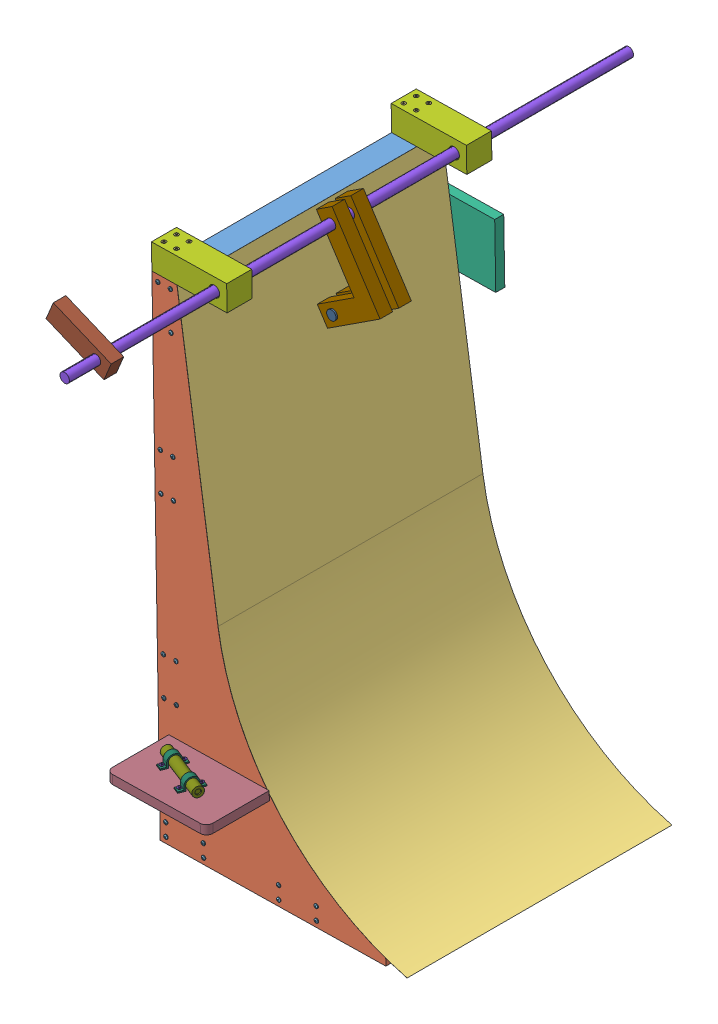
SolidWorks assembly Ramp System, configuration Default. Lengths in mm.
Overall size (518.53 1077.79 1143).
89 component instances, 19 part files, 30 mates.
Components (placement in the parent):
- Ramp-1: Ramp [Default] at (68.598 121.8193 472.884) size (517.11 999.07 560.24)
  - base support-1: base support [Default] at (50.3599 26.2618 18.2563) x (0.999855 0.017038 0) z (0 0 1) size (101.6 50.8 500)
  - base support-2: base support [Default] at (278.9267 30.1567 18.2563) x (0.999855 0.017038 0) z (0 0 1) size (101.6 50.8 500)
  - base support-3: base support [Default] at (9.3841 940.0963 18.2563) x (0.017038 -0.999855 0) z (0 0 1) size (101.6 50.8 500)
  - base support-4: base support [Default] at (14.3609 648.0387 18.2563) x (-0.017038 0.999855 0) z (0 0 1) size (101.6 50.8 500)
  - base support-5: base support [Default] at (20.4196 292.4904 18.2563) x (-0.017038 0.999855 0) z (0 0 1) size (101.6 50.8 500)
  - Ramp Right Side-2: Ramp Right Side [Default] at (0 0 518.2563) x (0.999855 0.017038 0) z (0 0 1) size (457.2 990.6 18.26)
  - ramp top-2: ramp top [Default] at (72.1988 -109.1723 0.0645) x (0.999855 0.017038 0) z (0 0 1) size (449.5 990.69 536.45)
  - Left Ramp Side-1: Left Ramp Side [Default] x (0.999855 0.017038 0) z (0 0 1) size (457.2 990.6 18.26)
  - Smaller Wood Screw-1: Smaller Wood Screw [93360A255] at (12.049 38.3109 517.4625) x (0 0 -1) z (0.99986 0.016723 0) size (40.83 7.98 7.98)
  - Smaller Wood Screw-2: Smaller Wood Screw [93360A255] at (88.238 39.6091 517.4625) x (0 0 -1) z (0.737932 -0.674875 0) size (40.83 7.98 7.98)
  - Smaller Wood Screw-3: Smaller Wood Screw [93360A255] at (12.4818 12.9145 517.4625) x (0 0 -1) z (0.728347 -0.685209 0) size (40.83 7.98 7.98)
  - Smaller Wood Screw-4: Smaller Wood Screw [93360A255] at (88.6707 14.2128 517.4625) x (0 0 -1) z (0.978218 -0.207583 0) size (40.83 7.98 7.98)
  - Smaller Wood Screw-5: Smaller Wood Screw [93360A255] at (240.6158 42.2057 517.4625) x (0 0 -1) z (0.895633 -0.444794 0) size (40.83 7.98 7.98)
  - Smaller Wood Screw-6: Smaller Wood Screw [93360A255] at (317.2375 18.1077 517.4625) x (0 0 -1) z (0.927956 -0.37269 0) size (40.83 7.98 7.98)
  - Smaller Wood Screw-7: Smaller Wood Screw [93360A255] at (241.0486 16.8094 517.4625) x (0 0 -1) z (0.947454 -0.319891 0) size (40.83 7.98 7.98)
  - Smaller Wood Screw-8: Smaller Wood Screw [93360A255] at (316.8048 43.504 517.4625) x (0 0 -1) z (0.916674 -0.399636 0) size (40.83 7.98 7.98)
  - Smaller Wood Screw-9: Smaller Wood Screw [93360A255] at (27.7082 610.1607 517.4625) x (0 0 -1) z (-0.434402 -0.900719 0) size (40.83 7.98 7.98)
  - Smaller Wood Screw-10: Smaller Wood Screw [93360A255] at (8.3705 254.1795 517.4625) x (0 0 -1) z (0.029195 -0.999574 0) size (40.83 7.98 7.98)
  - Smaller Wood Screw-11: Smaller Wood Screw [93360A255] at (2.3119 609.7279 517.4625) x (0 0 -1) z (-0.383207 -0.923662 0) size (40.83 7.98 7.98)
  - Smaller Wood Screw-12: Smaller Wood Screw [93360A255] at (33.7669 254.6123 517.4625) x (0 0 -1) z (-0.101676 -0.994818 0) size (40.83 7.98 7.98)
  - Smaller Wood Screw-13: Smaller Wood Screw [93360A255] at (32.4686 330.8012 517.0434) x (0 0 -1) z (0.798033 -0.602614 0) size (40.83 7.98 7.98)
  - Smaller Wood Screw-14: Smaller Wood Screw [93360A255] at (7.0723 330.3685 517.4625) x (0 0 -1) z (0.916528 -0.39997 0) size (40.83 7.98 7.98)
  - Smaller Wood Screw-15: Smaller Wood Screw [93360A255] at (22.7314 902.2183 517.4625) x (0 0 -1) z (0.94297 -0.332878 0) size (40.83 7.98 7.98)
  - Smaller Wood Screw-16: Smaller Wood Screw [93360A255] at (21.4332 978.4072 517.4625) x (0 0 -1) z (0.957808 -0.287409 0) size (40.83 7.98 7.98)
  - Smaller Wood Screw-17: Smaller Wood Screw [93360A255] at (26.4099 686.3496 517.4625) x (0 0 -1) z (0.9364 -0.350934 0) size (40.83 7.98 7.98)
  - Smaller Wood Screw-18: Smaller Wood Screw [93360A255] at (-2.6649 901.7855 517.4625) x (0 0 -1) z (0.929454 -0.368937 0) size (40.83 7.98 7.98)
  - Smaller Wood Screw-19: Smaller Wood Screw [93360A255] at (-3.9632 977.9744 517.4625) x (0 0 -1) z (0.716357 -0.697734 0) size (40.83 7.98 7.98)
  - Smaller Wood Screw-20: Smaller Wood Screw [93360A255] at (1.0136 685.9168 517.4625) x (0 0 -1) z (0.980156 -0.198228 0) size (40.83 7.98 7.98)
  - Smaller Wood Screw-21: Smaller Wood Screw [93360A255] at (21.4332 978.4072 19.05) x (0 0 1) z (-0.976976 0.213347 0) size (40.83 7.98 7.98)
  - Smaller Wood Screw-22: Smaller Wood Screw [93360A255] at (-2.6649 901.7855 19.05) x (0 0 1) z (-0.975802 0.218657 0) size (40.83 7.98 7.98)
  - Smaller Wood Screw-23: Smaller Wood Screw [93360A255] at (-3.9632 977.9744 19.05) x (0 0 1) z (-0.973932 0.22684 0) size (40.83 7.98 7.98)
  - Smaller Wood Screw-24: Smaller Wood Screw [93360A255] at (22.7314 902.2183 19.05) x (0 0 1) z (-0.980702 0.195508 0) size (40.83 7.98 7.98)
  - Smaller Wood Screw-25: Smaller Wood Screw [93360A255] at (1.0136 685.9168 19.05) x (0 0 1) z (-0.999462 -0.032793 0) size (40.83 7.98 7.98)
  - Smaller Wood Screw-26: Smaller Wood Screw [93360A255] at (2.3119 609.7279 19.05) x (0 0 1) z (-0.993805 0.11114 0) size (40.83 7.98 7.98)
  - Smaller Wood Screw-27: Smaller Wood Screw [93360A255] at (26.4099 686.3496 19.05) x (0 0 1) z (-0.996065 0.088627 0) size (40.83 7.98 7.98)
  - Smaller Wood Screw-28: Smaller Wood Screw [93360A255] at (27.7082 610.1607 19.05) x (0 0 1) z (-0.990107 0.140311 0) size (40.83 7.98 7.98)
  - Smaller Wood Screw-29: Smaller Wood Screw [93360A255] at (32.4686 330.8012 19.05) x (0 0 1) z (-0.984191 0.177108 0) size (40.83 7.98 7.98)
  - Smaller Wood Screw-30: Smaller Wood Screw [93360A255] at (8.3705 254.1795 19.05) x (0 0 1) z (-0.989085 0.147348 0) size (40.83 7.98 7.98)
  - Smaller Wood Screw-31: Smaller Wood Screw [93360A255] at (7.0723 330.3685 19.05) x (0 0 1) z (-0.990343 0.138636 0) size (40.83 7.98 7.98)
  - Smaller Wood Screw-32: Smaller Wood Screw [93360A255] at (33.7669 254.6123 19.05) x (0 0 1) z (-0.990372 0.138429 0) size (40.83 7.98 7.98)
  - Smaller Wood Screw-33: Smaller Wood Screw [93360A255] at (12.049 38.3109 19.05) x (0 0 1) z (-0.99641 0.084662 0) size (40.83 7.98 7.98)
  - Smaller Wood Screw-34: Smaller Wood Screw [93360A255] at (12.4818 12.9145 19.05) x (0 0 1) z (-0.902798 0.430064 0) size (40.83 7.98 7.98)
  - Smaller Wood Screw-35: Smaller Wood Screw [93360A255] at (88.238 39.6091 19.05) x (0 0 1) z (-0.346699 0.937977 0) size (40.83 7.98 7.98)
  - Smaller Wood Screw-36: Smaller Wood Screw [93360A255] at (88.6707 14.2128 19.05) x (0 0 1) z (-0.822189 0.569215 0) size (40.83 7.98 7.98)
  - Smaller Wood Screw-37: Smaller Wood Screw [93360A255] at (241.0486 16.8094 19.05) x (0 0 1) z (-0.485074 0.874473 0) size (40.83 7.98 7.98)
  - Smaller Wood Screw-38: Smaller Wood Screw [93360A255] at (316.8048 43.504 19.05) x (0 0 1) z (0.344552 0.938767 0) size (40.83 7.98 7.98)
  - Smaller Wood Screw-39: Smaller Wood Screw [93360A255] at (317.2375 18.1077 19.05) x (0 0 1) z (-0.659807 0.751435 0) size (40.83 7.98 7.98)
  - Smaller Wood Screw-40: Smaller Wood Screw [93360A255] at (240.6158 42.2057 19.05) x (0 0 1) z (-0.848855 0.528626 0) size (40.83 7.98 7.98)
  - Position Marker-1: Position Marker [Default] at (14.1597 889.3708 -18.2626) x (0.017024 -0.999855 0) z (0 0 1) size (127 127 18.26)
  - Smaller Wood Screw-41: Smaller Wood Screw [93360A255] at (39.9884 864.4069 0.7874) x (0 0 1) z (0.509818 0.860282 0) size (40.83 7.98 7.98)
  - Smaller Wood Screw-42: Smaller Wood Screw [93360A255] at (51.3172 788.3888 0.7874) x (0 0 1) z (0.395796 -0.918339 0) size (40.83 7.98 7.98)
- Release Mechanism-1: Release Mechanism [Default] at (46.9788 1061.4429 877.8659) x (0.999855 0.017038 0) z (0 0 1) size (224.2 244.6 1143)
  - Release support-1: Release support [Default] at (5.6069 50.7445 80.7306) x (0 0 1) z (-1 0 0) size (50.8 50.8 152.4)
  - Release support-2: Release support [Default] at (5.6069 50.7445 -404.9174) x (0 0 1) z (-1 0 0) size (50.8 50.8 152.4)
  - Release Dowel-1: Release Dowel [Default] at (132.6069 76.1445 -708.1934) size (19.05 19.05 1143)
  - RELEASE HOOK-1: RELEASE HOOK [Default] at (102.964 87.5183 -168.4434) x (0.531967 -0.846765 0) z (0 0 1) size (177.8 127 25.4)
  - RELEASE HOOK-2: RELEASE HOOK [Default] at (102.964 87.5183 -130.3434) x (0.531967 -0.846765 0) z (0 0 1) size (177.8 127 25.4)
  - Hook Dowel-1: Hook Dowel [Default] at (133.6443 -80.6855 -171.6184) size (19.05 19.05 69.85)
  - Release Lever-1: Release Lever [Default] at (47.1299 134.2749 345.9066) x (0 0 1) z (0.916371 -0.400331 0) size (25.4 38.1 127)
- Smaller Wood Screw-1: Smaller Wood Screw [93360A255] at (221.5714 289.9774 991.6165) x (0 0 -1) z (0.43744 -0.899248 0) size (40.83 7.98 7.98)
- Smaller Wood Screw-2: Smaller Wood Screw [93360A255] at (154.9786 270.425 991.6165) x (0 0 -1) z (0.100324 -0.994955 0) size (40.83 7.98 7.98)
- Smaller Wood Screw-3: Smaller Wood Screw [93360A255] at (137.2049 288.5398 991.6165) x (0 0 -1) z (0.854567 -0.519342 0) size (40.83 7.98 7.98)
- Smaller Wood Screw-4: Smaller Wood Screw [93360A255] at (239.3451 271.8626 991.6165) x (0 0 -1) z (-0.232923 -0.972495 0) size (40.83 7.98 7.98)
- Biggest Wood Screw-1: Biggest Wood Screw [90031A209] at (64.2006 1125.2756 996.6965) x (0.017038 -0.999855 0) z (-0.012431 -0.000212 0.999923) size (76.2 8.43 8.43)
- Biggest Wood Screw-3: Biggest Wood Screw [90031A209] at (89.5969 1125.7083 511.0485) x (0.017038 -0.999855 0) z (0 0 1) size (76.2 8.43 8.43)
- Biggest Wood Screw-4: Biggest Wood Screw [90031A209] at (89.5969 1125.7083 485.6485) x (0.017038 -0.999855 0) z (0 0 1) size (76.2 8.43 8.43)
- Biggest Wood Screw-5: Biggest Wood Screw [90031A209] at (64.2006 1125.2756 485.6485) x (0.017038 -0.999855 0) z (0 0 1) size (76.2 8.43 8.43)
- Biggest Wood Screw-6: Biggest Wood Screw [90031A209] at (64.2006 1125.2756 511.0485) x (0.017038 -0.999855 0) z (-0.495664 -0.008446 0.868473) size (76.2 8.43 8.43)
- Biggest Wood Screw-7: Biggest Wood Screw [90031A209] at (89.5969 1125.7083 971.2965) x (0.017038 -0.999855 0) z (0 0 1) size (76.2 8.43 8.43)
- Biggest Wood Screw-8: Biggest Wood Screw [90031A209] at (89.5969 1125.7083 996.6965) x (0.017038 -0.999855 0) z (0.075008 0.001278 0.997182) size (76.2 8.43 8.43)
- Biggest Wood Screw-9: Biggest Wood Screw [90031A209] at (64.2006 1125.2756 971.2965) x (0.017038 -0.999855 0) z (0 0 1) size (76.2 8.43 8.43)
- Assemsight-1: Assemsight [Default] at (228.4786 162.1389 1293.8106) x (-0.999855 -0.017038 0) z (0 0 -1) size (203.2 82.02 127)
  - RampSight-1: RampSight [Default] at (38.0656 138.4152 220.9267) size (203.2 17.78 127)
  - screwangle-1: screwangle [Default] at (-4.0031 138.4152 259.014) x (0 0 -1) z (0 -1 0) size (50.8 34.92 38.1)
  - screwangle-2: screwangle [Default] at (80.3757 138.4152 259.014) x (0 0 -1) z (0 -1 0) size (50.8 34.92 38.1)
  - LaserStrap-3: LaserStrap [Default] at (76.1001 166.1978 233.9353) x (0.37234 0 -0.928096) z (0.928096 0 0.37234) size (45.4 22.54 12.7)
  - LaserStrap-4: LaserStrap [Default] at (17.166 166.1978 210.2918) x (0.37234 0 -0.928096) z (0.928096 0 0.37234) size (45.4 22.54 12.7)
  - laserpointereal-3: laserpointereal [Default] at (-2.9774 166.1952 201.3092) x (-0.371391 0.071332 0.925732) z (0.928096 0 0.37234) size (30.2 30.2 115)
  - Part1^Assemsight-1: Part1^Assemsight [Default] at origin (virtual)
  - Part2^Assemsight-1: Part2^Assemsight [Default] at origin (virtual)
  - sightscrew-1: sightscrew [90031A194] at (16.8102 154.9836 228.2328) x (0 -1 0) z (-0.202266 0 0.979331) size (12.7 8.43 8.43)
  - sightscrew-2: sightscrew [90031A194] at (-12.7344 140.9552 245.9965) x (0 1 0) z (-0.546944 0 0.837169) size (12.7 8.43 8.43)
  - sightscrew-3: sightscrew [90031A194] at (88.8656 154.9836 219.1703) x (0 -1 0) z (-0.546944 0 0.837169) size (12.7 8.43 8.43)
  - sightscrew-4: sightscrew [90031A194] at (4.4741 140.9552 270.7615) x (0 1 0) z (-0.546944 0 0.837169) size (12.7 8.43 8.43)
  - sightscrew-5: sightscrew [90031A194] at (88.8529 140.9552 270.7615) x (0 1 0) z (-0.546944 0 0.837169) size (12.7 8.43 8.43)
  - sightscrew-7: sightscrew [90031A194] at (75.7444 154.9836 251.8764) x (0 -1 0) z (-0.546944 0 0.837169) size (12.7 8.43 8.43)
  - sightscrew-8: sightscrew [90031A194] at (71.6444 140.9552 245.9965) x (0 1 0) z (-0.546944 0 0.837169) size (12.7 8.43 8.43)
  - sightscrew-9: sightscrew [90031A194] at (29.9315 154.9836 195.5267) x (0 -1 0) z (-0.546944 0 0.837169) size (12.7 8.43 8.43)
Mates (geometry in assembly coordinates):
- Coincident7: coincident: plane of Ramp-1/Ramp Right Side-2 through (51.7203 1112.2755 1009.3965) normal (-0.017038 0.999855 0); plane of Release Mechanism-1/Release support-1 through (51.7203 1112.2755 1009.3965) normal (0.017038 -0.999855 0)
- Coincident8: coincident: line of Ramp-1/Ramp Right Side-2 through (51.7203 1112.2755 1009.3965) axis (0.999855 0.017038 0); line of Release Mechanism-1/Release support-1 through (51.7203 1112.2755 1009.3965) axis (0.999855 0.017038 0)
- Coincident9: coincident: line of Ramp-1/Ramp Right Side-2 through (51.7203 1112.2755 1009.3965) axis (0 0 -1); line of Release Mechanism-1/Release support-1 through (51.7203 1112.2755 1009.3965) axis (0 0 -1)
- Concentric7: concentric: cylinder of Release Mechanism-1/Release support-1 through (64.4184 1112.4919 996.6965) axis (-0.017038 0.999855 0) radius 1.5875; cylinder of Biggest Wood Screw-1 through (63.5514 1163.37 996.6965) axis (-0.017038 0.999855 0) radius 2.0828
- Coincident11: coincident: plane of Release Mechanism-1/Release support-1 through (50.8547 1163.0681 1009.3965) normal (-0.017038 0.999855 0); circle of Biggest Wood Screw-1
- Concentric8: concentric: cylinder of Release Mechanism-1/Release support-1 through (64.4184 1112.4919 971.2965) axis (-0.017038 0.999855 0) radius 1.5875; cylinder of Biggest Wood Screw-9 through (63.5514 1163.37 971.2965) axis (-0.017038 0.999855 0) radius 2.0828
- Coincident12: coincident: plane of Release Mechanism-1/Release support-1 through (50.8547 1163.0681 1009.3965) normal (-0.017038 0.999855 0); circle of Biggest Wood Screw-9
- Concentric9: concentric: cylinder of Release Mechanism-1/Release support-1 through (89.8147 1112.9246 996.6965) axis (-0.017038 0.999855 0) radius 1.5875; cylinder of Biggest Wood Screw-8 through (88.9478 1163.8028 996.6965) axis (-0.017038 0.999855 0) radius 2.0828
- Coincident14: coincident: plane of Release Mechanism-1/Release support-1 through (50.8547 1163.0681 1009.3965) normal (-0.017038 0.999855 0); circle of Biggest Wood Screw-8
- Concentric10: concentric: cylinder of Release Mechanism-1/Release support-1 through (89.8147 1112.9246 971.2965) axis (-0.017038 0.999855 0) radius 1.5875; cylinder of Biggest Wood Screw-7 through (88.9478 1163.8028 971.2965) axis (-0.017038 0.999855 0) radius 2.0828
- Coincident15: coincident: plane of Release Mechanism-1/Release support-1 through (50.8547 1163.0681 1009.3965) normal (-0.017038 0.999855 0); circle of Biggest Wood Screw-7
- Concentric11: concentric: cylinder of Release Mechanism-1/Release support-2 through (64.4184 1112.4919 511.0485) axis (-0.017038 0.999855 0) radius 1.5875; cylinder of Biggest Wood Screw-6 through (63.5514 1163.37 511.0485) axis (-0.017038 0.999855 0) radius 2.0828
- Coincident16: coincident: plane of Release Mechanism-1/Release support-2 through (50.8547 1163.0681 523.7485) normal (-0.017038 0.999855 0); circle of Biggest Wood Screw-6
- Concentric13: concentric: cylinder of Release Mechanism-1/Release support-2 through (64.4184 1112.4919 485.6485) axis (-0.017038 0.999855 0) radius 1.5875; cylinder of Biggest Wood Screw-5 through (63.5514 1163.37 485.6485) axis (-0.017038 0.999855 0) radius 2.0828
- Coincident17: coincident: plane of Release Mechanism-1/Release support-2 through (50.8547 1163.0681 523.7485) normal (-0.017038 0.999855 0); circle of Biggest Wood Screw-5
- Concentric14: concentric: circle of Release Mechanism-1/Release support-2; cylinder of Biggest Wood Screw-4 through (88.9478 1163.8028 485.6485) axis (-0.017038 0.999855 0) radius 2.0828
- Coincident18: coincident: plane of Release Mechanism-1/Release support-2 through (50.8547 1163.0681 523.7485) normal (-0.017038 0.999855 0); circle of Biggest Wood Screw-4
- Concentric15: concentric: cylinder of Release Mechanism-1/Release support-2 through (89.8147 1112.9246 511.0485) axis (-0.017038 0.999855 0) radius 1.5875; cylinder of Biggest Wood Screw-3 through (88.9478 1163.8028 511.0485) axis (-0.017038 0.999855 0) radius 2.0828
- Coincident19: coincident: plane of Release Mechanism-1/Release support-2 through (50.8547 1163.0681 523.7485) normal (-0.017038 0.999855 0); circle of Biggest Wood Screw-3
- Coincident22: coincident: plane of Ramp-1/Ramp Right Side-2 through (68.598 121.8193 1009.3965) normal (0 0 1); plane of Assemsight-1/screwangle-1 through (212.6846 299.0348 1009.3965) normal (0 0 -1)
- Concentric18: concentric: circle of Ramp-1/Ramp Right Side-2; circle of Assemsight-1/screwangle-1
- Parallel2: parallel: plane of Ramp-1/Ramp Right Side-2 through (68.598 121.8193 1009.3965) normal (0.017038 -0.999855 0); plane of Assemsight-1/RampSight-1 through (188.0602 299.8854 1072.8838) normal (0.017038 -0.999855 0)
- Concentric19: concentric: cylinder of Smaller Wood Screw-3 through (137.2049 288.5398 1010.6665) axis (0 0 1) radius 1.7443; cylinder of Assemsight-1/screwangle-2 through (137.2049 288.5398 973.8365) axis (0 0 1) radius 2.0828
- Coincident24: coincident: plane of Smaller Wood Screw-3 through (138.1108 290.0305 1010.6665) normal (0 0 -1); plane of Assemsight-1/screwangle-2 through (128.9455 260.7726 1010.6665) normal (0 0 1)
- Concentric20: concentric: cylinder of Smaller Wood Screw-2 through (154.9786 270.425 1010.6665) axis (0 0 1) radius 1.7443; circle of Assemsight-1/screwangle-2
- Coincident25: coincident: plane of Smaller Wood Screw-2 through (156.7141 270.6 1010.6665) normal (0 0 -1); plane of Assemsight-1/screwangle-2 through (128.9455 260.7726 1010.6665) normal (0 0 1)
- Concentric21: concentric: cylinder of Smaller Wood Screw-1 through (221.5714 289.9774 1010.6665) axis (0 0 1) radius 1.7443; circle of Assemsight-1/screwangle-1
- Coincident26: coincident: plane of Smaller Wood Screw-1 through (223.14 290.7405 1010.6665) normal (0 0 -1); plane of Assemsight-1/screwangle-1 through (213.3121 262.2102 1010.6665) normal (0 0 1)
- Concentric22: concentric: cylinder of Smaller Wood Screw-4 through (239.3451 271.8626 1010.6665) axis (0 0 1) radius 1.7443; cylinder of Assemsight-1/screwangle-1 through (239.3451 271.8626 973.8365) axis (0 0 1) radius 2.0828
- Coincident27: coincident: plane of Smaller Wood Screw-4 through (241.0415 271.4563 1010.6665) normal (0 0 -1); plane of Assemsight-1/screwangle-1 through (213.3121 262.2102 1010.6665) normal (0 0 1)
